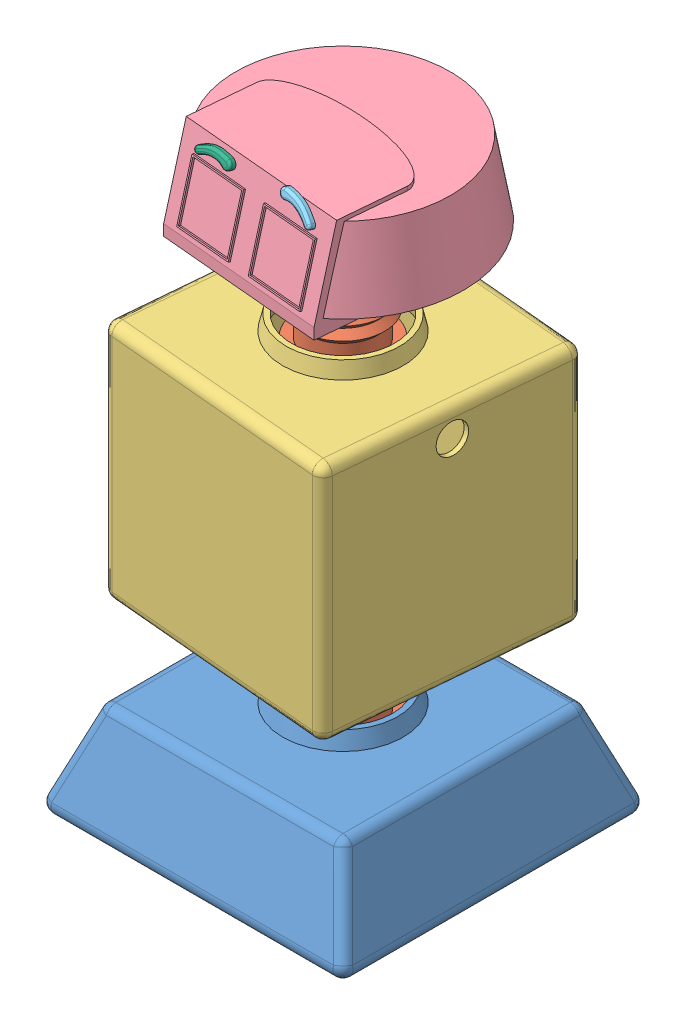
SolidWorks assembly Square Assembly, configuration Default. Lengths in mm.
Overall size (300.59 598.96 300.59).
7 component instances, 6 part files, 13 mates.
Components (placement in the parent):
- SquareBase-1: SquareBase [Default] at origin size (300.59 110 300.59)
- TepidNeck-1: TepidNeck [Default] at (120 90 120) x (0.992212 0 -0.124561) z (0.124561 0 0.992212) size (90 100 90)
- SquareBody-1: SquareBody [Default] at (109.2839 320 239.5206) x (0.089301 0 -0.996005) z (0.996005 0 0.089301) size (240 270 240)
- TepidNeck-2: TepidNeck [Default] at (120 410 120) size (90 100 90)
- SquareGuyHead-1: SquareGuyHead [Default] at (120 415 120) x (-0.089301 0 0.996005) z (-0.996005 0 -0.089301) size (216.08 109 240)
- LeftBrow-1: LeftBrow [Default] at (173.2021 478.6575 198.5039) x (0.952077 -0.265515 0.151828) z (-0.086648 0.241922 0.966419) size (38.5 19 15.55)
- RightBrow-1: RightBrow [Default] at (53.6815 478.6575 187.7878) x (0.996006 0.000065 0.089284) z (-0.086648 0.241922 0.966419) size (38.5 19 15.55)
Mates (geometry in assembly coordinates):
- Concentric1: concentric aligned: circle of SquareBase-1; circle of TepidNeck-1
- Concentric2: concentric anti-aligned: circle of TepidNeck-1; circle of SquareBody-1
- Concentric4: concentric anti-aligned: circle of SquareBody-1; circle of TepidNeck-2
- Concentric5: concentric aligned: cylinder of TepidNeck-2 through (120 410 120) axis (0 1 0) radius 35; circle of TepidHead-1
- Coincident2: coincident aligned: plane of TepidNeck-2 through (165 405 120) normal (0 -1 0); circle of TepidHead-1
- Parallel2: parallel aligned: plane of SquareBody-1 through (228.8045 320 250.2366) normal (-0.089301 0 0.996005); plane of SquareGuyHead-1 through (230.9958 411 225.7959) normal (-0.089301 0 0.996005)
- Coincident4: coincident anti-aligned: plane of SquareBody-1 through (228.8045 315 250.2366) normal (0 -1 0); plane of TepidNeck-2 through (165 315 120) normal (0 1 0)
- Coincident5: coincident anti-aligned: plane of TepidNeck-1 through (164.6495 85 114.3947) normal (0 -1 0); plane of SquareBody-1 through (228.8045 85 250.2366) normal (0 1 0)
- Coincident6: coincident anti-aligned: plane of SquareBase-1 through (0 -5 0) normal (0 -1 0); plane of TepidNeck-1 through (164.6495 -5 114.3947) normal (0 1 0)
- Coincident7: coincident anti-aligned: plane of SquareGuyHead-1 through (233.2771 492.7904 200.3523) normal (0.086648 -0.241922 -0.966419); plane of RightBrow-1 through (53.6815 478.6575 187.7878) normal (-0.086648 0.241922 0.966419)
- Concentric7: concentric anti-aligned: cylinder of SquareGuyHead-1 through (53.6815 478.6575 187.7878) axis (-0.086648 0.241922 0.966419) radius 2; cylinder of RightBrow-1 through (53.2483 479.8671 192.6199) axis (0.086648 -0.241922 -0.966419) radius 2.125
- Coincident8: coincident anti-aligned: plane of SquareGuyHead-1 through (233.2771 492.7904 200.3523) normal (0.086648 -0.241922 -0.966419); plane of LeftBrow-1 through (173.2021 478.6575 198.5039) normal (-0.086648 0.241922 0.966419)
- Concentric8: concentric anti-aligned: cylinder of SquareGuyHead-1 through (173.2021 478.6575 198.5039) axis (-0.086648 0.241922 0.966419) radius 2; cylinder of LeftBrow-1 through (172.7689 479.8671 203.336) axis (0.086648 -0.241922 -0.966419) radius 2.125
